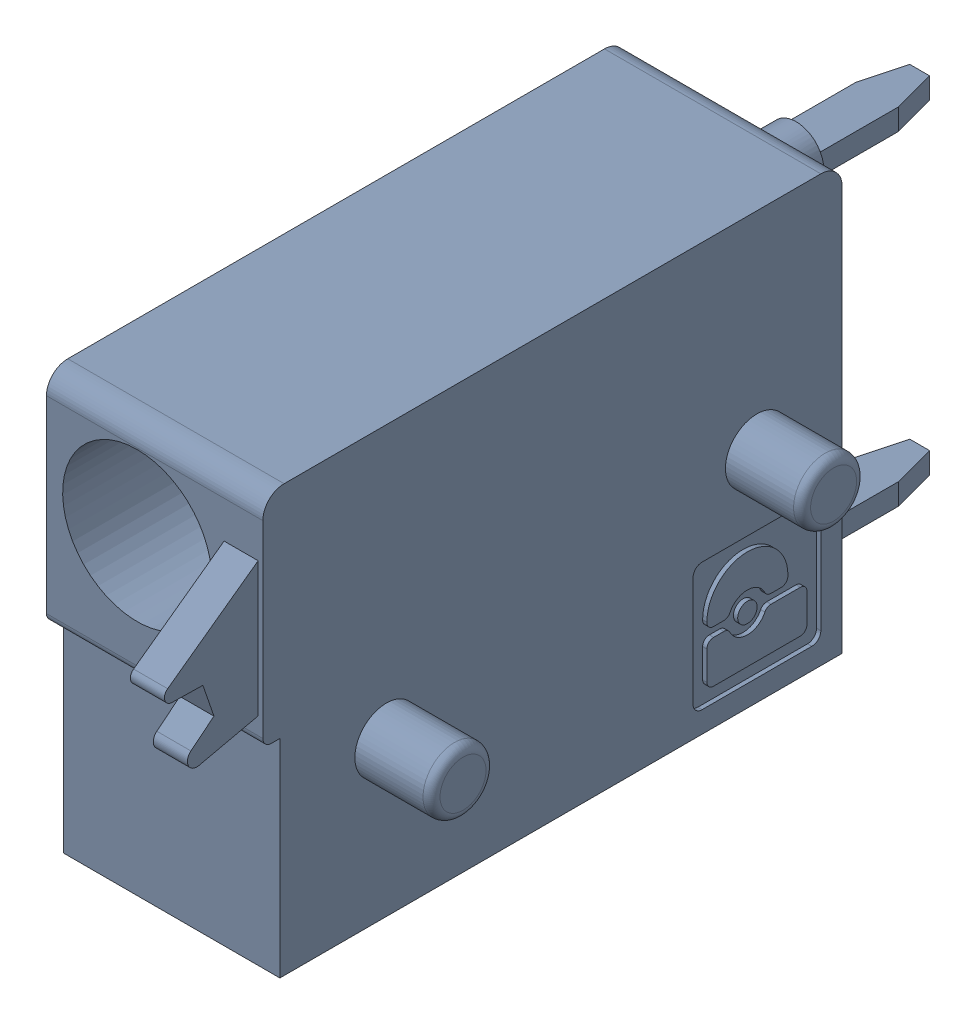
SolidWorks assembly J81, configuration Default. Lengths in mm.
Overall size (6.88 10 19.2).
2 component instances, 1 part files, 0 mates.
Components (placement in the parent):
- 1790348-1: 1790348 [Default] at (233.0451 -7.6199 0) x (0 1 0) z (1 0 0) size (10 19.2 6.88)
  - ffkds-v2-5.08-1: ffkds-v2-5.08 [Default] at (-23.7414 -38.158 -2.54) x (0 -1 0) z (0 0 1) size (19.2 10 6.88)
